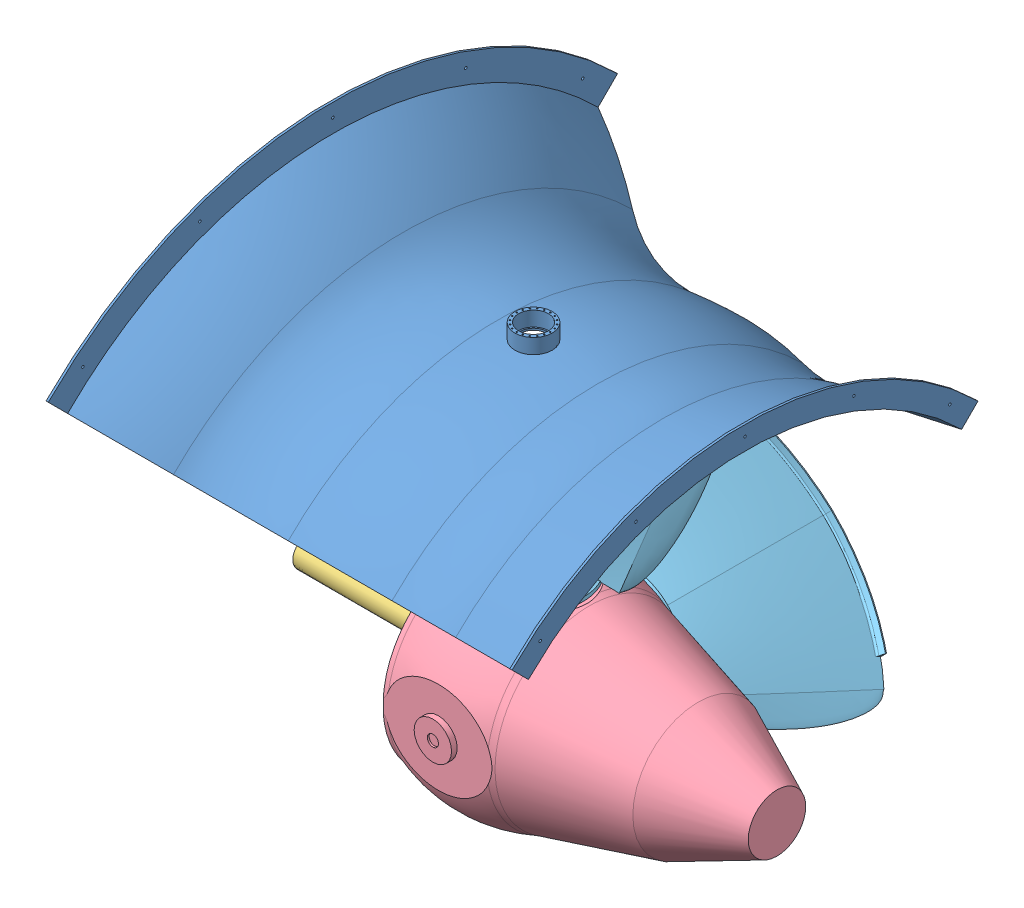
SolidWorks assembly Montagem_Maquete_REV A, configuration Valor predeterminado. Lengths in mm.
Overall size (4973.09 4973.09 6234.64).
26 component instances, 11 part files, 32 mates.
Components (placement in the parent):
- Aro_Camara-2: Aro_Camara [Valor predeterminado] at origin size (1106.8 535.11 1520.28)
- Disco-1: Disco [Valor predeterminado] at origin size (10 496 496)
- Eixo-1: Eixo [Valor predeterminado] at (-605 0 0) x (1 0 0) z (0 0.214688 0.976683) size (600 76.2 76.2)
- Rotor_REV A-1: Rotor_REV A [Valor predeterminado] at origin size (797.49 580.04 537.79)
- Pa_da_Turbina_REV A-1: Pa_da_Turbina_REV A [Valor predeterminado<Como usinado>] at (0 228.8953 0) x (0.707107 0 0.707107) z (-0.707107 0 0.707107) size (1330 2890.82 5703.01)
- Flange-2: Flange [Valor predeterminado] at (-5 0 0) x (0 1 0) z (0 0 1) size (192.8 44.8 192.8)
- Placa_de_Fixacao-2: Placa_de_Fixacao [Valor predeterminado] at (-552 350 0) x (0 -1 0) z (1 0 0) size (1500 1800 10) (hidden)
- Placa_Suporte-1: Placa_Suporte [Valor predeterminado] at (564.8 -400 0) x (0 0 -1) z (1 0 0) size (1800 1300 10) (hidden)
- Placa_Base-1: Placa_Base [Valor predeterminado] at (11.4 -430 5) x (0 0 -1) z (1 0 0) size (1790 30 1126.8) (hidden)
- Pa_da_Turbina_REV A-2: Pa_da_Turbina_REV A [Valor predeterminado<Como usinado>] at (0 0 -228.8953) x (0.707107 0.707107 0) z (-0.707107 0.707107 0) size (1330 2890.82 5703.01)
- socket head cap screw_din-2: socket head cap screw_din [DIN 912 M6 x 30 --- 30N] at (-24.8 73.7 0) size (36 10 10)
- hex nut style 1 gradeab_din-1: hex nut style 1 gradeab_din [Hexagon Nut ISO 4032 - M6 - D - N] at (10.2 73.7 0) x (0 0 -1) z (1 0 0) size (10 11.55 5.2)
- hex nut style 1 gradeab_din-2: hex nut style 1 gradeab_din [Hexagon Nut ISO 4032 - M6 - D - N] at (10.2 0 -73.7) x (0 -1 0) z (1 0 0) size (10 11.55 5.2)
- hex nut style 1 gradeab_din-3: hex nut style 1 gradeab_din [Hexagon Nut ISO 4032 - M6 - D - N] at (10.2 -73.7 0) x (0 0 1) z (1 0 0) size (10 11.55 5.2)
- hex nut style 1 gradeab_din-4: hex nut style 1 gradeab_din [Hexagon Nut ISO 4032 - M6 - D - N] at (10.2 0 73.7) x (0 1 0) z (1 0 0) size (10 11.55 5.2)
- socket head cap screw_din-3: socket head cap screw_din [DIN 912 M6 x 30 --- 30N] at (-24.8 0 -73.7) x (1 0 0) z (0 1 0) size (36 10 10)
- socket head cap screw_din-4: socket head cap screw_din [DIN 912 M6 x 30 --- 30N] at (-24.8 -73.7 0) x (1 0 0) z (0 0 -1) size (36 10 10)
- socket head cap screw_din-5: socket head cap screw_din [DIN 912 M6 x 30 --- 30N] at (-24.8 0 73.7) x (1 0 0) z (0 -1 0) size (36 10 10)
- socket head cap screw_din-10: socket head cap screw_din [DIN 912 M6 x 25 --- 25N] at (-11 240.8953 0) x (1 0 0) z (0 0.980922 0.194404) size (31 10 10)
- hex nut style 1 gradeab_din-5: hex nut style 1 gradeab_din [Hexagon Nut ISO 4032 - M6 - D - N] at (19.5436 240.8953 0) x (0 0 -1) z (1 0 0) size (10 11.55 5.2)
- socket head cap screw_din-11: socket head cap screw_din [DIN 912 M6 x 25 --- 25N] at (-11 0 -240.8953) x (1 0 0) z (0 0.194404 -0.980922) size (31 10 10)
- socket head cap screw_din-12: socket head cap screw_din [DIN 912 M6 x 25 --- 25N] at (-11 -240.8953 0) x (1 0 0) z (0 -0.980922 -0.194404) size (31 10 10)
- socket head cap screw_din-13: socket head cap screw_din [DIN 912 M6 x 25 --- 25N] at (-11 0 240.8953) x (1 0 0) z (0 -0.194404 0.980922) size (31 10 10)
- hex nut style 1 gradeab_din-6: hex nut style 1 gradeab_din [Hexagon Nut ISO 4032 - M6 - D - N] at (19.5436 0 -240.8953) x (0 -1 0) z (1 0 0) size (10 11.55 5.2)
- hex nut style 1 gradeab_din-7: hex nut style 1 gradeab_din [Hexagon Nut ISO 4032 - M6 - D - N] at (19.5436 -240.8953 0) x (0 0 1) z (1 0 0) size (10 11.55 5.2)
- hex nut style 1 gradeab_din-8: hex nut style 1 gradeab_din [Hexagon Nut ISO 4032 - M6 - D - N] at (19.5436 0 240.8953) x (0 1 0) z (1 0 0) size (10 11.55 5.2)
Mates (geometry in assembly coordinates):
- Coincidente24: coincident: point of ?
- Coincidente25: coincident aligned: plane of Rotor_REV A-1 through (0 0 0) normal (1 0 0); plane of assembly through (0 0 0) normal (1 0 0)
- Paralelo1: parallel anti-aligned: plane of Rotor_REV A-1 through (50 253.8953 0) normal (0 1 0); plane of Pa_da_Turbina_REV A-1 through (-35.3553 254.0253 35.3553) normal (0 -1 0)
- Ângulo1: planar angle = 0.785398 rad aligned: plane of Rotor_REV A-1 through (0 0 0) normal (0 0 1); plane of Pa_da_Turbina_REV A-1 through (0 228.8953 0) normal (-0.707107 0 0.707107)
- Concêntrico7: concentric aligned: cylinder of Rotor_REV A-1 through (0 -141.1401 0) axis (0 -1 0) radius 50; cylinder of Pa_da_Turbina_REV A-1 through (0 228.8953 0) axis (0 -1 0) radius 133
- Concêntrico5: concentric aligned: circle of Aro_Camara-2; cylinder of Placa_de_Fixacao-2 through (-552 0 0) axis (1 0 0) radius 40
- Coincidente27: coincident anti-aligned: plane of Aro_Camara-2 through (-542 706.7317 -706.7317) normal (-1 0 0); plane of Placa_de_Fixacao-2 through (-542 350 0) normal (1 0 0)
- Coincidente28: coincident aligned: plane of Rotor_REV A-1 through (0 0 0) normal (0 1 0); plane of assembly through (0 0 0) normal (0 1 0)
- Concêntrico6: concentric anti-aligned: cylinder of Placa_de_Fixacao-2 through (-552 0 0) axis (1 0 0) radius 40; cylinder of Eixo-1 through (-605 0 0) axis (-1 0 0) radius 38.1
- Concêntrico82: concentric anti-aligned: cylinder of Eixo-1 through (-605 0 0) axis (-1 0 0) radius 33.3; cylinder of Flange-2 through (-5 0 0) axis (1 0 0) radius 38.1
- Coincidente302: coincident anti-aligned: plane of Disco-1 through (-5 248 0) normal (-1 0 0); plane of Flange-2 through (-5 38.1 0) normal (1 0 0)
- Concêntrico831: concentric aligned: cylinder of Flange-2 through (-18.8 73.7 0) axis (-1 0 0) radius 3.3; cylinder of socket head cap screw_din-2 through (-56.55 73.7 0) axis (-1 0 0) radius 5
- Coincidente3031: coincident anti-aligned: plane of Flange-2 through (-18.8 96.4 0) normal (-1 0 0); plane of socket head cap screw_din-2 through (-18.8 78.7 0) normal (1 0 0)
- Concêntrico84: concentric anti-aligned: cylinder of Disco-1 through (-18.8 73.7 0) axis (-1 0 0) radius 3.3; cylinder of hex nut style 1 gradeab_din-1 through (-14.8375 73.7 0) axis (1 0 0) radius 3
- Coincidente304: coincident anti-aligned: plane of Disco-1 through (5 248 0) normal (1 0 0); plane of hex nut style 1 gradeab_din-1 through (5 73.7 10) normal (-1 0 0)
- Coincidente3033: coincident anti-aligned: plane of Disco-1 through (-5 248 0) normal (-1 0 0); plane of Eixo-1 through (-5 37.2116 -8.1796) normal (1 0 0)
- Concêntrico833: concentric anti-aligned: circle of Aro_Camara-2; circle of Placa_Suporte-1
- Coincidente3034: coincident anti-aligned: plane of Aro_Camara-2 through (564.8 582.0366 -582.0366) normal (1 0 0); plane of Placa_Suporte-1 through (564.8 0 0) normal (-1 0 0)
- Coincidente3035: coincident anti-aligned: plane of Placa_de_Fixacao-2; plane of assembly through (0 0 0) normal (0 0 1)
- Coincidente3036: coincident anti-aligned: plane of Rotor_REV A-1 through (15 268.8953 0) normal (0 1 0); plane of Pa_da_Turbina_REV A-1 through (-35.3553 268.8953 35.3553) normal (0 -1 0)
- Coincidente3037: coincident anti-aligned: plane of Placa_de_Fixacao-2 through (-542 -400 900) normal (0 -1 0); plane of Placa_Base-1 through (11.4 -400 5) normal (0 1 0)
- Coincidente3038: coincident: plane of Placa_de_Fixacao-2 through (-542 1100 900) normal (0 0 1); line of Placa_Base-1 through (-552 -400 900) axis (1 0 0)
- Coincidente3039: coincident aligned: plane of Placa_de_Fixacao-2 through (-552 350 0) normal (-1 0 0); plane of Placa_Base-1 through (-552 -400 900) normal (-1 0 0)
- Coincidente3040: coincident anti-aligned: plane of Placa_Suporte-1 through (564.8 -400 0) normal (0 0 -1); plane of assembly through (0 0 0) normal (0 0 1)
- Concêntrico8341: concentric anti-aligned: cylinder of Disco-1 through (14.3436 240.8953 0) axis (1 0 0) radius 3.3; cylinder of socket head cap screw_din-10 through (-42.75 240.8953 0) axis (-1 0 0) radius 5
- Coincidente30411: coincident anti-aligned: plane of Disco-1 through (-5 248 0) normal (-1 0 0); plane of socket head cap screw_din-10 through (-5 241.8673 -4.9046) normal (1 0 0)
- Coincidente30421: coincident anti-aligned: plane of Rotor_REV A-1 through (14.3436 232.8953 0) normal (1 0 0); plane of hex nut style 1 gradeab_din-5 through (14.3436 240.8953 10) normal (-1 0 0)
- Concêntrico836: concentric anti-aligned: cylinder of socket head cap screw_din-10 through (-42.75 240.8953 0) axis (-1 0 0) radius 3; cylinder of hex nut style 1 gradeab_din-5 through (14.3436 240.8953 0) axis (1 0 0) radius 2.5
- Concêntrico8342: concentric anti-aligned: cylinder of Eixo-1 through (-605 0 0) axis (-1 0 0) radius 38.1; cylinder of ? through (-552 0 0) axis (1 0 0) radius 50
- Coincidente30422: coincident anti-aligned: plane of Placa_de_Fixacao-2 through (-552 350 0) normal (-1 0 0); plane of ? through (-552 36.2412 -11.7551) normal (1 0 0)
- Concêntrico8343: concentric aligned: cylinder of Eixo-1 through (-605 0 0) axis (-1 0 0) radius 38.1; cylinder of ? through (-542 0 0) axis (-1 0 0) radius 38.1
- Coincidente30423: coincident anti-aligned: plane of Placa_de_Fixacao-2 through (-542 350 0) normal (1 0 0); plane of ? through (-542 -24.7031 29.0064) normal (-1 0 0)
